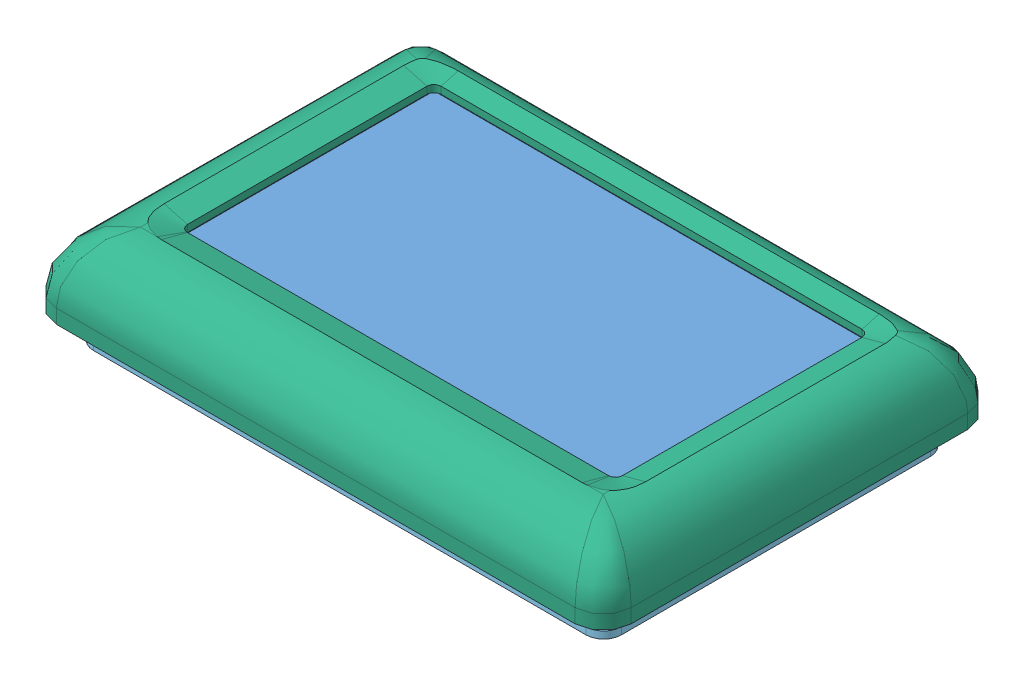
SolidWorks assembly Mikromedia PLus Assembly, configuration 001. Lengths in mm.
Overall size (130.18 22.37 88.9).
7 component instances, 6 part files, 21 mates.
Components (placement in the parent):
- Mikromedia Plus for STM32-1: Mikromedia Plus for STM32 [001] at origin size (119.53 6.67 78)
- B37BA208-FEBA-42A1-A9AA-39896B944AF7-1: B37BA208-FEBA-42A1-A9AA-39896B944AF7 [001] at (44.7662 0 -33.1017) x (1 0 0) z (0 0 -1) size (10.7 4.95 9.2)
- 26 pin header-1: 26 pin header [001] at (0.0127 0 -36.758) size (66.04 11.2 2.5)
- 26 pin header-2: 26 pin header [001] at (0.0127 0 36.758) size (66.04 11.2 2.5)
- User Library-PIN HEADER FEMALE 8-1: User Library-PIN HEADER FEMALE 8 [001] at (-31.7373 -10.84 36.758) size (20.32 8.3 2.54)
- Mikromedia Plus for STM32 shield-1: Mikromedia Plus for STM32 shield [001] at (0 -12.4275 0) size (119.53 1.59 78)
- logger housing top-1: logger housing top [001] at (0 -6.0325 0) size (130.18 15.97 88.9)
Mates (geometry in assembly coordinates):
- Coincident1: coincident aligned: plane of Mikromedia Plus for STM32-1 through (0 0 0) normal (1 0 0); plane of assembly through (0 0 0) normal (1 0 0)
- Coincident2: coincident aligned: plane of Mikromedia Plus for STM32-1 through (0 0 0) normal (0 1 0); plane of assembly through (0 0 0) normal (0 1 0)
- Coincident3: coincident aligned: plane of Mikromedia Plus for STM32-1 through (0 0 0) normal (0 0 1); plane of assembly through (0 0 0) normal (0 0 1)
- Coincident4: coincident anti-aligned: plane of Mikromedia Plus for STM32-1 through (59.7662 0 -39.0017) normal (0 -1 0); plane of B37BA208-FEBA-42A1-A9AA-39896B944AF7-1 through (48.6162 0 -35.4017) normal (0 1 0)
- Distance1: distance = 15 mm aligned: plane of B37BA208-FEBA-42A1-A9AA-39896B944AF7-1; plane of Mikromedia Plus for STM32-1 through (59.7662 1.5875 39.0017) normal (1 0 0)
- Coincident6: coincident aligned: plane of Mikromedia Plus for STM32-1 through (-59.7662 1.5875 -39.0017) normal (0 0 -1); plane of B37BA208-FEBA-42A1-A9AA-39896B944AF7-1 through (40.9162 -3.45 -39.0017) normal (0 0 -1)
- Coincident7: coincident aligned: cylinder of Mikromedia Plus for STM32-1 through (-31.7373 -0.001 -36.758) axis (0 1 0) radius 0.508; circle of 26 pin header-1
- Coincident8: coincident aligned: cylinder of Mikromedia Plus for STM32-1 through (-31.7373 -0.001 36.758) axis (0 1 0) radius 0.508; circle of 26 pin header-2
- Coincident9: coincident anti-aligned: plane of Mikromedia Plus for STM32-1 through (59.7662 0 -39.0017) normal (0 -1 0); plane of 26 pin header-2 through (-31.6373 0 36.7611) normal (0 1 0)
- Parallel1: parallel aligned: plane of 26 pin header-2 through (0.0127 0 36.758) normal (0 0 1); plane of assembly through (0 0 0) normal (0 0 1)
- Coincident10: coincident anti-aligned: plane of Mikromedia Plus for STM32-1 through (59.7662 0 -39.0017) normal (0 -1 0); plane of 26 pin header-1 through (-31.6373 0 -36.7549) normal (0 1 0)
- Parallel2: parallel aligned: plane of Mikromedia Plus for STM32-1 through (0 0 0) normal (0 0 1); plane of 26 pin header-1 through (0.0127 0 -36.758) normal (0 0 1)
- Concentric1: concentric aligned: cylinder of Mikromedia Plus for STM32-1 through (-31.7373 -0.001 36.758) axis (0 1 0) radius 0.508; circle of User Library-PIN HEADER FEMALE 8-1
- Parallel3: parallel aligned: plane of Mikromedia Plus for STM32-1 through (-59.7662 1.5875 39.0017) normal (0 0 1); plane of User Library-PIN HEADER FEMALE 8-1 through (-30.4673 -2.54 38.028) normal (0 0 1)
- Coincident11: coincident anti-aligned: plane of 26 pin header-2 through (-31.6373 -2.54 36.7611) normal (0 -1 0); plane of User Library-PIN HEADER FEMALE 8-1 through (-33.0073 -2.54 38.028) normal (0 1 0)
- Concentric2: concentric aligned: cylinder of Mikromedia Plus for STM32-1 through (-31.7373 -0.001 36.758) axis (0 1 0) radius 0.508; cylinder of Mikromedia Plus for STM32 shield-1 through (-31.7373 -12.4285 36.758) axis (0 1 0) radius 0.508
- Parallel4: parallel aligned: plane of Mikromedia Plus for STM32-1 through (-59.7662 1.5875 39.0017) normal (0 0 1); plane of Mikromedia Plus for STM32 shield-1 through (-59.7662 -10.84 39.0017) normal (0 0 1)
- Coincident13: coincident anti-aligned: plane of User Library-PIN HEADER FEMALE 8-1 through (-33.0073 -10.84 38.028) normal (0 -1 0); plane of Mikromedia Plus for STM32 shield-1 through (59.7662 -10.84 -39.0017) normal (0 1 0)
- Coincident14: coincident anti-aligned: plane of Mikromedia Plus for STM32-1 through (-52.6662 6.6675 33.1983) normal (0 1 0); plane of logger housing top-1 through (61.9125 6.6675 -41.275) normal (0 -1 0)
- Width1: width anti-aligned: plane of logger housing top-1 through (-61.9125 6.6675 41.275) normal (1 0 0); plane of logger housing top-1 through (61.9125 6.6675 41.275) normal (-1 0 0); plane of Mikromedia Plus for STM32-1 through (-59.7662 1.5875 39.0017) normal (-1 0 0); plane of Mikromedia Plus for STM32-1 through (59.7662 1.5875 39.0017) normal (1 0 0)
- Width2: width aligned: plane of Mikromedia Plus for STM32-1 through (-59.7662 1.5875 -39.0017) normal (0 0 -1); plane of Mikromedia Plus for STM32-1 through (-59.7662 1.5875 39.0017) normal (0 0 1); plane of logger housing top-1 through (-61.9125 6.6675 41.275) normal (0 0 -1); plane of logger housing top-1 through (-61.9125 6.6675 -41.275) normal (0 0 1)
